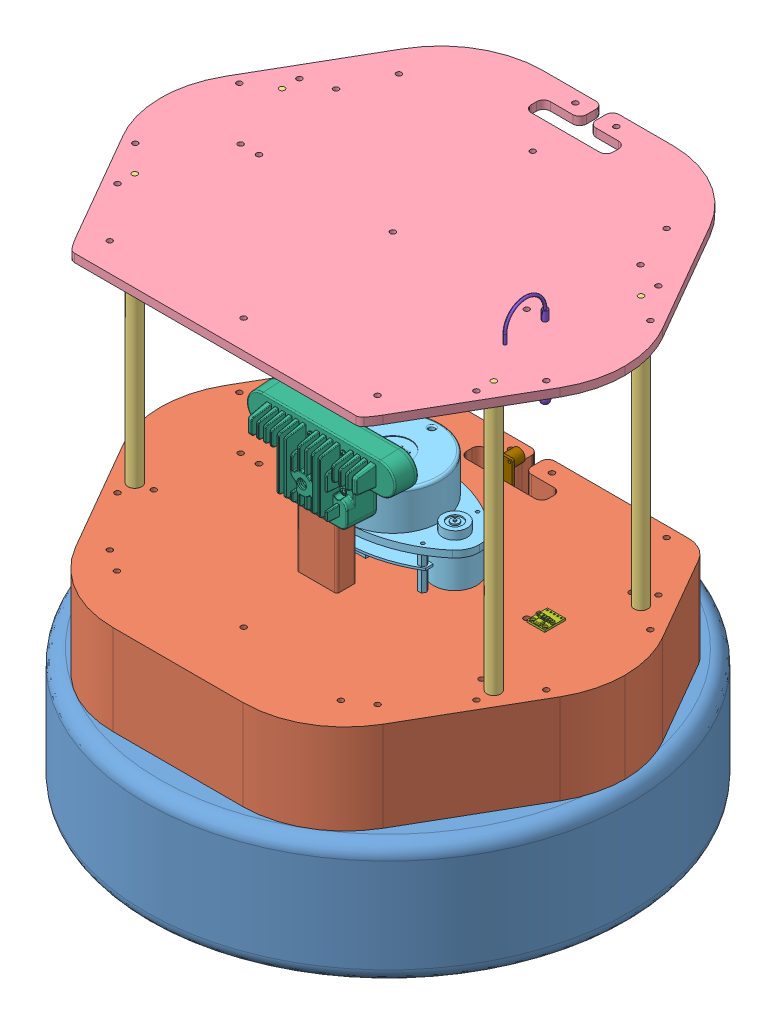
SolidWorks assembly Turtlebot4Assem, configuration Default. Lengths in mm.
Overall size (354 373.83 354).
12 component instances, 9 part files, 24 mates.
Components (placement in the parent):
- Kobuki Base-1: Kobuki Base [Default] at (151.4984 129.222 268.9926) size (354 89 354)
- Layer A-1: Layer A [Default] at (151.4984 278.222 265.3926) size (340 111 267.27)
- ROD-1: ROD [Default] at (282.8984 218.222 322.8926) x (-0.326124 0 0.945327) z (-0.945327 0 -0.326124) size (10 262 10)
- ROD-2: ROD [Default] at (282.8984 218.222 215.0926) x (0.242222 0 0.970221) z (-0.970221 0 0.242222) size (10 262 10)
- ROD-3: ROD [Default] at (20.0984 218.222 322.8926) x (0.560447 0 0.828191) z (-0.828191 0 0.560447) size (10 262 10)
- ROD-4: ROD [Default] at (20.0984 218.222 215.0926) size (10 262 10)
- Layer C-1: Layer C [Default] at (151.4984 474.222 265.3926) size (340 6 287.27)
- rplidar_main-1: rplidar_main [По умолчанию] at (165.7484 308.822 265.3942) size (98.5 57.7 70.02)
- OAK-D-parts-14sep2020.stp-3: OAK-D-parts-14sep2020.stp [Default] at (149.808 370.0152 305.3942) x (-1 0 0) z (0 0 -1) size (110 54.5 33.05)
- OSNOVANIE.stp-1: OSNOVANIE.stp [Default] at (251.9304 284.222 252.7128) x (0.999998 0 -0.001829) z (0 1 0) size (13.1 15 3.05)
- ds18b20.step-1: ds18b20.step [Default] at (262.9536 452.1028 265.3927) x (0.021057 0 0.999778) z (0 -1 0) size (34.1 6 75.95)
- MLX90640-1: MLX90640 [Default] at (151.6042 285.7214 186.3926) x (-1 0 0) z (0 0 -1) size (16.02 28.28 13.12)
Mates (geometry in assembly coordinates):
- Concentric1: concentric anti-aligned: cylinder of Kobuki Base-1 through (282.8984 199.222 215.0926) axis (0 1 0) radius 1.975; cylinder of Layer A-1 through (282.8984 218.222 215.0926) axis (0 -1 0) radius 1.9748
- Concentric2: concentric anti-aligned: cylinder of Kobuki Base-1 through (282.8984 199.222 322.8926) axis (0 1 0) radius 1.975; cylinder of Layer A-1 through (282.8984 218.222 322.8926) axis (0 -1 0) radius 1.9748
- Concentric3: concentric anti-aligned: cylinder of Kobuki Base-1 through (282.8984 199.222 322.8926) axis (0 1 0) radius 1.975; cylinder of ROD-1 through (282.8984 480.222 322.8926) axis (0 -1 0) radius 5
- Coincident1: coincident anti-aligned: plane of Kobuki Base-1 through (151.4984 218.222 268.9926) normal (0 1 0); plane of ROD-1 through (282.8984 218.222 322.8926) normal (0 -1 0)
- Concentric4: concentric anti-aligned: cylinder of Kobuki Base-1 through (282.8984 199.222 215.0926) axis (0 1 0) radius 1.975; cylinder of ROD-2 through (282.8984 480.222 215.0926) axis (0 -1 0) radius 5
- Coincident2: coincident anti-aligned: plane of Kobuki Base-1 through (151.4984 218.222 268.9926) normal (0 1 0); plane of ROD-2 through (282.8984 218.222 215.0926) normal (0 -1 0)
- Concentric5: concentric anti-aligned: circle of Kobuki Base-1; cylinder of ROD-3 through (20.0984 480.222 322.8926) axis (0 -1 0) radius 5
- Coincident3: coincident anti-aligned: plane of Kobuki Base-1 through (151.4984 218.222 268.9926) normal (0 1 0); plane of ROD-3 through (20.0984 218.222 322.8926) normal (0 -1 0)
- Coincident4: coincident anti-aligned: plane of Kobuki Base-1 through (151.4984 218.222 268.9926) normal (0 1 0); plane of ROD-4 through (20.0984 218.222 215.0926) normal (0 -1 0)
- Concentric6: concentric anti-aligned: cylinder of Kobuki Base-1 through (20.0984 199.222 215.0926) axis (0 1 0) radius 1.975; cylinder of ROD-4 through (20.0984 480.222 215.0926) axis (0 -1 0) radius 5
- Distance1: distance = 155 mm anti-aligned: plane of Layer A-1 through (-15.9458 284.222 245.9812) normal (0 1 0); plane of Kobuki Base-1 through (151.4984 129.222 268.9926) normal (0 -1 0)
- Concentric8: concentric aligned: cylinder of ROD-2 through (282.8984 480.222 215.0926) axis (0 -1 0) radius 5; cylinder of Layer C-1 through (282.8984 474.222 215.0926) axis (0 -1 0) radius 1.9748
- Concentric9: concentric aligned: cylinder of ROD-1 through (282.8984 480.222 322.8926) axis (0 -1 0) radius 5; cylinder of Layer C-1 through (282.8984 474.222 322.8926) axis (0 -1 0) radius 1.9748
- Distance2: distance = 351 mm anti-aligned: plane of Layer C-1 through (260.6195 480.222 390.4182) normal (0 1 0); plane of Kobuki Base-1 through (151.4984 129.222 268.9926) normal (0 -1 0)
- Concentric10: concentric anti-aligned: circle of Layer A-1; circle of rplidar_main-1
- Coincident5: coincident anti-aligned: plane of Layer A-1 through (-15.9458 284.222 245.9812) normal (0 1 0); plane of rplidar_main-1 through (165.7484 284.222 265.3942) normal (0 -1 0)
- Parallel1: parallel anti-aligned: plane of Layer A-1 through (121.4984 284.222 186.3926) normal (1 0 0); plane of rplidar_main-1 through (141.6502 293.222 295.3942) normal (-1 0 0)
- Concentric12: concentric anti-aligned: circle of Layer A-1; cylinder of OSNOVANIE.stp-1 through (262.9536 284.222 265.3927) axis (0 1 0) radius 1.5
- Coincident18: coincident anti-aligned: plane of Layer A-1 through (-15.9458 284.222 245.9812) normal (0 1 0); plane of OSNOVANIE.stp-1 through (258.4941 284.222 260.2008) normal (0 -1 0)
- Parallel7: parallel aligned: plane of Layer A-1 through (164.5286 362.0354 317.6581) normal (0.999998 0 -0.001829); plane of OSNOVANIE.stp-1 through (265.0578 284.222 267.6888) normal (0.999998 0 -0.001829)
- Concentric13: concentric anti-aligned: circle of Layer C-1; circle of ds18b20.step-1
- Coincident23: coincident anti-aligned: plane of Layer A-1 through (181.4984 284.222 186.3926) normal (0 0 -1); plane of MLX90640-1 through (144.5942 298.8614 186.3926) normal (0 0 1)
- Parallel11: parallel anti-aligned: line of Layer A-1 through (176.4737 284.222 186.3926) axis (-1 0 0); line of MLX90640-1 through (144.5942 299.8614 184.6126) axis (1 0 0)
- Lock1: lock: unknown of Layer A-1; unknown of MLX90640-1
